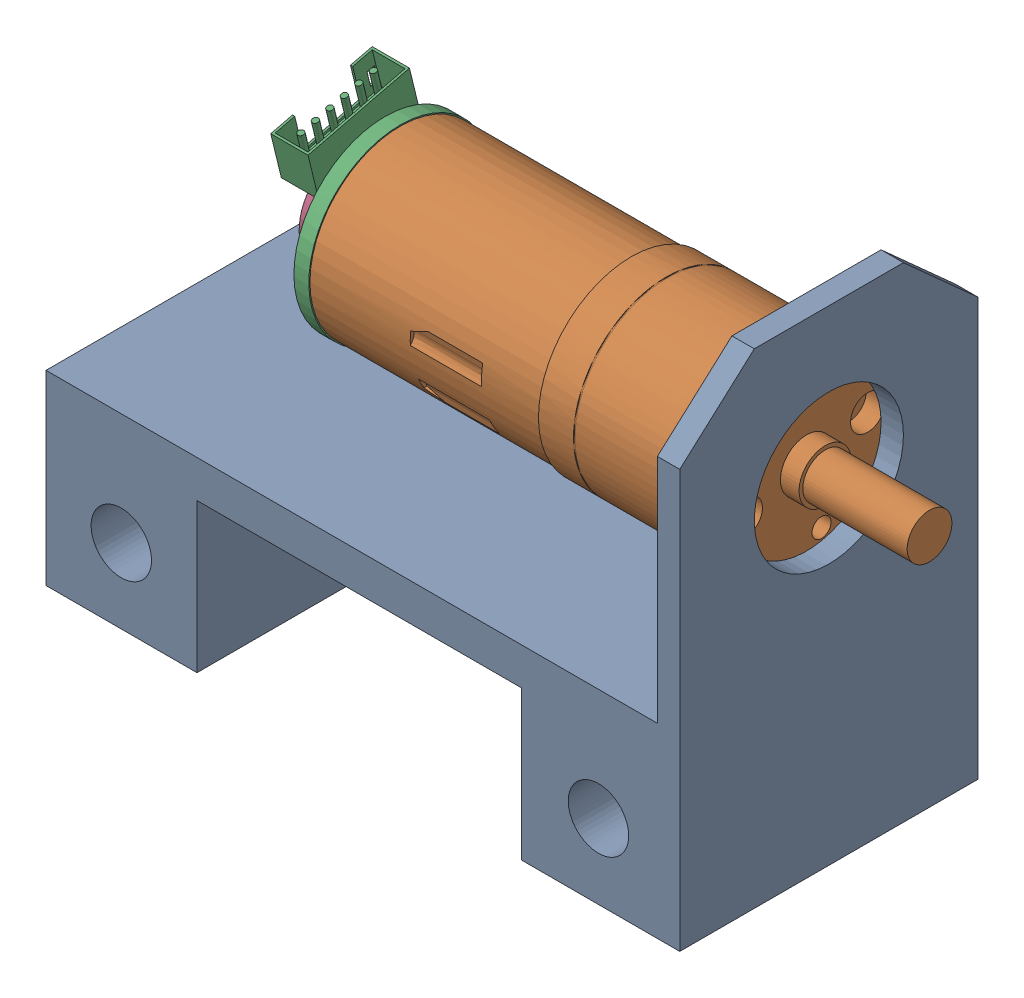
SolidWorks assembly ensamble movil, configuration Predeterminado. Lengths in mm.
Overall size (98.5 65 40).
2 component instances, 2 part files, 5 mates.
Components (placement in the parent):
- P-movil-1: P-movil [Predeterminado] at (42 12.5 0) size (85 65 40)
- PoLoLu 1 (1)-1: PoLoLu 1 (1) [Predeterminado] at (46.1243 115.9261 -5.2546) x (-1 0 0) z (0 -0.971503 -0.237026) size (78.4 24.9 27.45)
Mates (geometry in assembly coordinates):
- Coincidente1: coincident anti-aligned: plane of P-movil-1 through (0 12.5 -40) normal (-1 0 0)
- Coincidente2: coincident aligned: plane of P-movil-1 through (42 12.5 0) normal (0 0 1)
- Coincidente3: coincident anti-aligned: plane of P-movil-1 through (42 0 -40) normal (0 -1 0)
- Concéntrica1: concentric anti-aligned: cylinder of P-movil-1 through (0 45 -20) axis (1 0 0) radius 10; cylinder of PoLoLu 1 (1)-1 through (106.9853 45 -20) axis (-1 0 0) radius 3
- Coincidente4: coincident anti-aligned: plane of P-movil-1 through (82 12.5 0) normal (-1 0 0); plane of PoLoLu 1 (1)-1 through (82 45 -20) normal (1 0 0)
